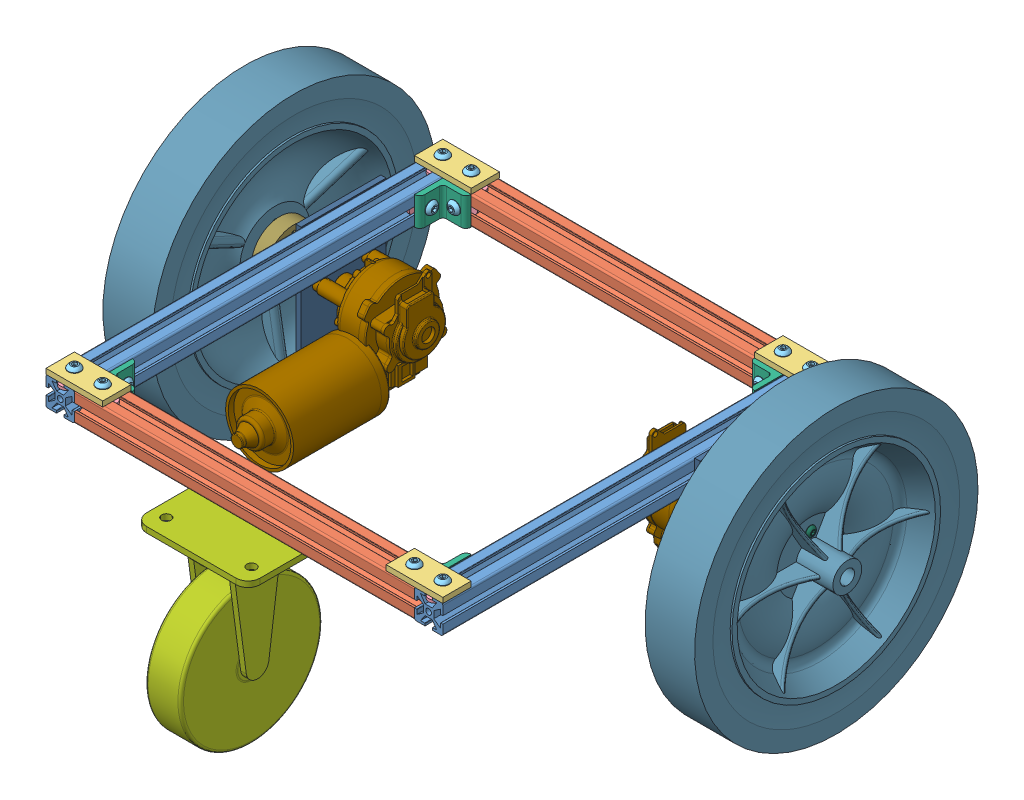
SolidWorks assembly Mobile Platform and Wheels, configuration Default. Lengths in mm.
Overall size (859.25 364.25 511.67).
92 component instances, 15 part files, 61 mates.
Components (placement in the parent):
- mobile platform-1: mobile platform [Default] at (-34.0492 217.8282 272.4297) size (581.47 166.45 355.6)
  - 80-20 Extrusion- 14in-1: 80-20 Extrusion- 14in [80-20 Extrusion - 12.0 inch] at (360.9878 12.7 -25.4) size (25.4 25.4 355.6)
  - 80-20 Extrusion -12in-1: 80-20 Extrusion -12in [80-20 Extrusion - 12.0 inch] at (348.2878 12.7 317.5) x (0 0 1) z (-1 0 0) size (25.4 25.4 304.8)
  - 80-20 Extrusion -12in-2: 80-20 Extrusion -12in [80-20 Extrusion - 12.0 inch] at (348.2878 12.7 -12.7) x (0 0 1) z (-1 0 0) size (25.4 25.4 304.8)
  - 80-20 Straight Degree Bracket Assy-2: 80-20 Straight Degree Bracket Assy [Default] at (308.9247 -2.3915 0.8462) x (0 0 -1) z (1 0 0) size (25.4 16.05 50.8)
    - 80-20 Straight Bracket-1: 80-20 Straight Bracket [Default] at (0.8462 27.7915 64.7631) size (25.4 4.76 50.8)
    - 80-20 0.25-20 T-NUT-1: 80-20 0.25-20 T-NUT [Default] at (139.4792 22.117 145.0157) x (0 0 -1) z (0 1 0) size (25.4 11.25 2.41)
    - 0.25-20 Button Head Cap Screw (BHCS)-1: 0.25-20 Button Head Cap Screw (BHCS) [Default] at (13.5462 35.9068 26.6631) x (1 0 0) z (0 -1 0) size (11.1 11.1 16.05)
    - 0.25-20 Button Head Cap Screw (BHCS)-2: 0.25-20 Button Head Cap Screw (BHCS) [Default] at (13.5462 35.9068 52.0631) x (-0.336886 0 -0.941545) z (0 -1 0) size (11.1 11.1 16.05)
    - 80-20 0.25-20 T-NUT-2: 80-20 0.25-20 T-NUT [Default] at (131.8987 22.8031 -73.87) x (-1 0 0) z (0 1 0) size (25.4 11.25 2.41)
  - 80-20 Straight Degree Bracket Assy-3: 80-20 Straight Degree Bracket Assy [Default] at (308.9247 -2.3915 331.0462) x (0 0 -1) z (1 0 0) size (25.4 16.05 50.8)
    - 80-20 Straight Bracket-1: 80-20 Straight Bracket [Default] at (0.8462 27.7915 64.7631) size (25.4 4.76 50.8)
    - 80-20 0.25-20 T-NUT-1: 80-20 0.25-20 T-NUT [Default] at (139.4792 22.117 145.0157) x (0 0 -1) z (0 1 0) size (25.4 11.25 2.41)
    - 0.25-20 Button Head Cap Screw (BHCS)-1: 0.25-20 Button Head Cap Screw (BHCS) [Default] at (13.5462 35.9068 26.6631) x (1 0 0) z (0 -1 0) size (11.1 11.1 16.05)
    - 0.25-20 Button Head Cap Screw (BHCS)-2: 0.25-20 Button Head Cap Screw (BHCS) [Default] at (13.5462 35.9068 52.0631) x (-0.336886 0 -0.941545) z (0 -1 0) size (11.1 11.1 16.05)
    - 80-20 0.25-20 T-NUT-2: 80-20 0.25-20 T-NUT [Default] at (131.8987 22.8031 -73.87) x (-1 0 0) z (0 1 0) size (25.4 11.25 2.41)
  - 80-20 90 Degree Bracket Assy-1: 80-20 90 Degree Bracket Assy [Default] at (41.0093 16.2711 -8.6086) x (0 -1 0) z (0 0 1) size (25.4 35.88 33.34)
    - 80-20 90 Degree Angle Bracket-1: 80-20 90 Degree Angle Bracket [Default] at (-9.1289 2.4785 8.6086) size (25.4 25.4 25.4)
    - 0.25-20 Button Head Cap Screw (BHCS)-1: 0.25-20 Button Head Cap Screw (BHCS) [Default] at (3.5711 10.5938 23.8486) x (1 0 0) z (0 -1 0) size (11.1 11.1 16.05)
    - 0.25-20 Button Head Cap Screw (BHCS)-2: 0.25-20 Button Head Cap Screw (BHCS) [Default] at (3.5711 17.7185 16.7239) x (1 0 0) z (0 0 -1) size (11.1 11.1 16.05)
    - 80-20 0.25-20 T-NUT-2: 80-20 0.25-20 T-NUT [Default] at (-122.3619 -100.634 5.3515) x (0 1 0) z (0 0 -1) size (25.4 11.25 2.41)
  - 80-20 90 Degree Bracket Assy-2: 80-20 90 Degree Bracket Assy [Default] at (356.8964 9.1289 307.2785) x (0 1 0) z (-1 0 0) size (25.4 35.88 33.34)
    - 80-20 90 Degree Angle Bracket-1: 80-20 90 Degree Angle Bracket [Default] at (-9.1289 2.4785 8.6086) size (25.4 25.4 25.4)
    - 0.25-20 Button Head Cap Screw (BHCS)-1: 0.25-20 Button Head Cap Screw (BHCS) [Default] at (3.5711 10.5938 23.8486) x (1 0 0) z (0 -1 0) size (11.1 11.1 16.05)
    - 0.25-20 Button Head Cap Screw (BHCS)-2: 0.25-20 Button Head Cap Screw (BHCS) [Default] at (3.5711 17.7185 16.7239) x (1 0 0) z (0 0 -1) size (11.1 11.1 16.05)
    - 80-20 0.25-20 T-NUT-2: 80-20 0.25-20 T-NUT [Default] at (-122.3619 -100.634 5.3515) x (0 1 0) z (0 0 -1) size (25.4 11.25 2.41)
  - 80-20 90 Degree Bracket Assy-3: 80-20 90 Degree Bracket Assy [Default] at (350.7663 9.1289 -8.6086) x (0 1 0) z (0 0 1) size (25.4 35.88 33.34)
    - 80-20 90 Degree Angle Bracket-1: 80-20 90 Degree Angle Bracket [Default] at (-9.1289 2.4785 8.6086) size (25.4 25.4 25.4)
    - 0.25-20 Button Head Cap Screw (BHCS)-1: 0.25-20 Button Head Cap Screw (BHCS) [Default] at (3.5711 10.5938 23.8486) x (1 0 0) z (0 -1 0) size (11.1 11.1 16.05)
    - 0.25-20 Button Head Cap Screw (BHCS)-2: 0.25-20 Button Head Cap Screw (BHCS) [Default] at (3.5711 17.7185 16.7239) x (1 0 0) z (0 0 -1) size (11.1 11.1 16.05)
    - 80-20 0.25-20 T-NUT-2: 80-20 0.25-20 T-NUT [Default] at (-122.3619 -100.634 5.3515) x (0 1 0) z (0 0 -1) size (25.4 11.25 2.41)
  - 80-20 90 Degree Bracket Assy-4: 80-20 90 Degree Bracket Assy [Default] at (35.9499 16.2711 307.2785) x (0 -1 0) z (1 0 0) size (25.4 35.88 33.34)
    - 80-20 90 Degree Angle Bracket-1: 80-20 90 Degree Angle Bracket [Default] at (-9.1289 2.4785 8.6086) size (25.4 25.4 25.4)
    - 0.25-20 Button Head Cap Screw (BHCS)-1: 0.25-20 Button Head Cap Screw (BHCS) [Default] at (3.5711 10.5938 23.8486) x (1 0 0) z (0 -1 0) size (11.1 11.1 16.05)
    - 0.25-20 Button Head Cap Screw (BHCS)-2: 0.25-20 Button Head Cap Screw (BHCS) [Default] at (3.5711 17.7185 16.7239) x (1 0 0) z (0 0 -1) size (11.1 11.1 16.05)
    - 80-20 0.25-20 T-NUT-2: 80-20 0.25-20 T-NUT [Default] at (-122.3619 -100.634 5.3515) x (0 1 0) z (0 0 -1) size (25.4 11.25 2.41)
  - 80-20 Extrusion- 14in-2: 80-20 Extrusion- 14in [80-20 Extrusion - 12.0 inch] at (30.7878 12.7 -25.4) size (25.4 25.4 355.6)
  - 80-20 Straight Degree Bracket Assy-4: 80-20 Straight Degree Bracket Assy [Default] at (82.8509 -2.3915 -26.2462) x (0 0 1) z (-1 0 0) size (25.4 16.05 50.8)
    - 80-20 Straight Bracket-1: 80-20 Straight Bracket [Default] at (0.8462 27.7915 64.7631) size (25.4 4.76 50.8)
    - 80-20 0.25-20 T-NUT-1: 80-20 0.25-20 T-NUT [Default] at (139.4792 22.117 145.0157) x (0 0 -1) z (0 1 0) size (25.4 11.25 2.41)
    - 0.25-20 Button Head Cap Screw (BHCS)-1: 0.25-20 Button Head Cap Screw (BHCS) [Default] at (13.5462 35.9068 26.6631) x (1 0 0) z (0 -1 0) size (11.1 11.1 16.05)
    - 0.25-20 Button Head Cap Screw (BHCS)-2: 0.25-20 Button Head Cap Screw (BHCS) [Default] at (13.5462 35.9068 52.0631) x (-0.336886 0 -0.941545) z (0 -1 0) size (11.1 11.1 16.05)
    - 80-20 0.25-20 T-NUT-2: 80-20 0.25-20 T-NUT [Default] at (131.8987 22.8031 -73.87) x (-1 0 0) z (0 1 0) size (25.4 11.25 2.41)
  - 80-20 Straight Degree Bracket Assy-5: 80-20 Straight Degree Bracket Assy [Default] at (82.8509 -2.3915 303.9538) x (0 0 1) z (-1 0 0) size (25.4 16.05 50.8)
    - 80-20 Straight Bracket-1: 80-20 Straight Bracket [Default] at (0.8462 27.7915 64.7631) size (25.4 4.76 50.8)
    - 80-20 0.25-20 T-NUT-1: 80-20 0.25-20 T-NUT [Default] at (139.4792 22.117 145.0157) x (0 0 -1) z (0 1 0) size (25.4 11.25 2.41)
    - 0.25-20 Button Head Cap Screw (BHCS)-1: 0.25-20 Button Head Cap Screw (BHCS) [Default] at (13.5462 35.9068 26.6631) x (1 0 0) z (0 -1 0) size (11.1 11.1 16.05)
    - 0.25-20 Button Head Cap Screw (BHCS)-2: 0.25-20 Button Head Cap Screw (BHCS) [Default] at (13.5462 35.9068 52.0631) x (-0.336886 0 -0.941545) z (0 -1 0) size (11.1 11.1 16.05)
    - 80-20 0.25-20 T-NUT-2: 80-20 0.25-20 T-NUT [Default] at (131.8987 22.8031 -73.87) x (-1 0 0) z (0 1 0) size (25.4 11.25 2.41)
  - 80-20 0.25-20 T-NUT-1: 80-20 0.25-20 T-NUT [Default] at (214.6952 -113.2331 306.9864) size (25.4 11.25 2.41)
  - 80-20 0.25-20 T-NUT-2: 80-20 0.25-20 T-NUT [Default] at (-58.5541 -113.2331 306.9864) size (25.4 11.25 2.41)
  - 80-20 0.25-20 T-NUT-3: 80-20 0.25-20 T-NUT [Default] at (41.3014 -113.2331 -103.1126) x (0 0 1) z (-1 0 0) size (25.4 11.25 2.41)
  - 80-20 0.25-20 T-NUT-4: 80-20 0.25-20 T-NUT [Default] at (350.4742 -113.2331 133.5926) x (0 0 -1) z (1 0 0) size (25.4 11.25 2.41)
- 0.25-20 Button Head Cap Screw (BHCS)-1: 0.25-20 Button Head Cap Screw (BHCS) [Default] at (-24.0767 230.5282 316.8797) x (0 -0.87127 -0.490804) z (1 0 0) size (11.1 11.1 16.05)
- 0.25-20 Button Head Cap Screw (BHCS)-2: 0.25-20 Button Head Cap Screw (BHCS) [Default] at (-24.0767 230.5282 354.9797) x (0 -0.925607 -0.378485) z (1 0 0) size (11.1 11.1 16.05)
- 0.25-20 Button Head Cap Screw (BHCS)-3: 0.25-20 Button Head Cap Screw (BHCS) [Default] at (347.7539 230.5282 319.7734) x (0 0.895902 0.444252) z (-1 0 0) size (11.1 11.1 16.05)
- 0.25-20 Button Head Cap Screw (BHCS)-4: 0.25-20 Button Head Cap Screw (BHCS) [Default] at (347.7539 230.5282 357.8734) x (0 0.519927 -0.854211) z (-1 0 0) size (11.1 11.1 16.05)
- 80-20 0.25-20 T-NUT-1: 80-20 0.25-20 T-NUT [Default] at (337.4522 104.5951 201.4209) x (0 0 1) z (-1 0 0) size (25.4 11.25 2.41)
- 80-20 0.25-20 T-NUT-2: 80-20 0.25-20 T-NUT [Default] at (-13.775 104.5951 435.2323) x (0 0 -1) z (1 0 0) size (25.4 11.25 2.41)
- 80-20 0.25-20 T-NUT-3: 80-20 0.25-20 T-NUT [Default] at (-13.775 104.5951 473.3323) x (0 0 -1) z (1 0 0) size (25.4 11.25 2.41)
- 80-20 0.25-20 T-NUT-4: 80-20 0.25-20 T-NUT [Default] at (337.4522 356.4612 476.226) x (0 0 -1) z (-1 0 0) size (25.4 11.25 2.41)
- Caster Wheel-1: Caster Wheel [Default] at (161.8386 217.8282 612.0617) x (-1 0 0) z (0 0 1) size (101.6 160.02 127)
- 80-20 0.25-20 T-NUT-5: 80-20 0.25-20 T-NUT [Default] at (5.2717 222.3788 463.7893) x (1 0 0) z (0 -1 0) size (25.4 11.25 2.41)
- 80-20 0.25-20 T-NUT-6: 80-20 0.25-20 T-NUT [Default] at (81.7003 222.3788 463.7893) x (1 0 0) z (0 -1 0) size (25.4 11.25 2.41)
- 0.25X20- 0.375in Cap Screw-1: 0.25X20- 0.375in Cap Screw [97763A262] at (123.6243 209.3954 589.7224) x (-0.984842 0 0.173455) z (0 -1 0) size (11.1 11.1 13.11)
- 0.25X20- 0.375in Cap Screw-2: 0.25X20- 0.375in Cap Screw [97763A262] at (200.0529 209.3954 589.7224) x (0.999999 0 -0.001416) z (0 -1 0) size (11.1 11.1 13.11)
- Enstort Bracket + Wheel Hub Assembly-1: Enstort Bracket + Wheel Hub Assembly [Entstort Bracket + Wheel Hub Assembly] at (136.9487 78.0176 331.0106) x (0 0 1) z (-1 0 0) size (175.66 126.24 332.48)
  - motor bracket assembly-1: motor bracket assembly [Default] at (-11.3939 -3.7311 8.9529) size (175.66 126.24 116.01)
    - 44 RPM Entstort Right Angle Gear Motor-1: 44 RPM Entstort Right Angle Gear Motor [Default] at (75.065 73.1836 102.1742) size (170.1 101.53 116.01)
    - bracket motor mount-1: bracket motor mount [Default] at (-21.7871 168.9416 143.9572) x (0 -1 0) z (0 0 1) size (101.6 76.2 4.76)
    - M6X1mm-10mm Hex Head-1: M6X1mm-10mm Hex Head [91287A133] at (39.7568 118.1416 145.7197) x (0 0 -1) z (-0.053654 -0.99856 0) size (14 11.55 10)
    - M6X1mm-10mm Hex Head-2: M6X1mm-10mm Hex Head [91287A133] at (-4.2372 118.1416 145.7197) x (0 0 -1) z (0.587181 -0.809455 0) size (14 11.55 10)
    - M6X1mm-10mm Hex Head-3: M6X1mm-10mm Hex Head [91287A133] at (17.7598 80.0416 145.7197) x (0 0 -1) z (0.923728 0.383049 0) size (14 11.55 10)
  - Wheel Hub-1: Wheel Hub [Default] at (6.3659 101.7105 208.8272) x (-1 0 0) z (0 0 -1) size (50.8 50.8 38.1)
  - M8 Hex Nut-1: M8 Hex Nut [90592A022] at (6.3659 101.7105 189.2172) size (13 15.01 6.5)
- Enstort Bracket + Wheel Hub Assembly-2: Enstort Bracket + Wheel Hub Assembly [Entstort Bracket + Wheel Hub Assembly] at (186.7285 78.0176 343.7425) x (0 0 -1) z (1 0 0) size (175.66 126.24 332.48)
  - motor bracket assembly-1: motor bracket assembly [Default] at (-11.3939 -3.7311 8.9529) size (175.66 126.24 116.01)
    - 44 RPM Entstort Right Angle Gear Motor-1: 44 RPM Entstort Right Angle Gear Motor [Default] at (75.065 73.1836 102.1742) size (170.1 101.53 116.01)
    - bracket motor mount-1: bracket motor mount [Default] at (-21.7871 168.9416 143.9572) x (0 -1 0) z (0 0 1) size (101.6 76.2 4.76)
    - M6X1mm-10mm Hex Head-1: M6X1mm-10mm Hex Head [91287A133] at (39.7568 118.1416 145.7197) x (0 0 -1) z (-0.053654 -0.99856 0) size (14 11.55 10)
    - M6X1mm-10mm Hex Head-2: M6X1mm-10mm Hex Head [91287A133] at (-4.2372 118.1416 145.7197) x (0 0 -1) z (0.587181 -0.809455 0) size (14 11.55 10)
    - M6X1mm-10mm Hex Head-3: M6X1mm-10mm Hex Head [91287A133] at (17.7598 80.0416 145.7197) x (0 0 -1) z (0.923728 0.383049 0) size (14 11.55 10)
  - Wheel Hub-1: Wheel Hub [Default] at (6.3659 101.7105 208.8272) x (-1 0 0) z (0 0 -1) size (50.8 50.8 38.1)
  - M8 Hex Nut-1: M8 Hex Nut [90592A022] at (6.3659 101.7105 189.2172) size (13 15.01 6.5)
- 10 Inch Wheel-1: 10 Inch Wheel [Default] at (-86.0518 179.7282 337.3766) x (-1 0 0) z (0 -0.5 0.866025) size (54.2 254 254)
- 10 Inch Wheel-2: 10 Inch Wheel [Default] at (409.7289 179.7282 337.3766) x (1 0 0) z (0 -0.5 0.866025) size (54.2 254 254)
- 10X24 -0.75in Cap Screw-1: 10X24 -0.75in Cap Screw [97763A337] at (-82.699 170.2032 353.8744) x (0 0.124315 -0.992243) z (-1 0 0) size (9.17 9.17 21.8)
- 10X24 -0.75in Cap Screw-2: 10X24 -0.75in Cap Screw [97763A337] at (-82.699 170.2032 320.8788) x (0 0.987183 -0.159589) z (-1 0 0) size (9.17 9.17 21.8)
- 10X24 -0.75in Cap Screw-3: 10X24 -0.75in Cap Screw [97763A337] at (-82.699 198.7782 337.3766) x (0 0.987183 -0.159589) z (-1 0 0) size (9.17 9.17 21.8)
- 10X24 -0.75in Cap Screw-4: 10X24 -0.75in Cap Screw [97763A337] at (406.3761 170.2032 353.8744) x (0 -0.05419 -0.998531) z (1 0 0) size (9.17 9.17 21.8)
- 10X24 -0.75in Cap Screw-5: 10X24 -0.75in Cap Screw [97763A337] at (406.3761 198.7782 337.3766) x (0 -0.05419 -0.998531) z (1 0 0) size (9.17 9.17 21.8)
- 10X24 -0.75in Cap Screw-6: 10X24 -0.75in Cap Screw [97763A337] at (406.3761 170.2032 320.8788) x (0 -0.05419 -0.998531) z (1 0 0) size (9.17 9.17 21.8)
Mates (geometry in assembly coordinates):
- Concentric6: concentric anti-aligned: cylinder of 0.25-20 Button Head Cap Screw (BHCS)-1 through (-8.0239 230.5282 316.8797) axis (-1 0 0) radius 3.175; cylinder of 80-20 0.25-20 T-NUT-2 through (-13.776 230.5282 316.8797) axis (1 0 0) radius 3.175
- Parallel3: parallel: line of 80-20 0.25-20 T-NUT-2 through (-13.775 236.1543 309.8058) axis (0 0 1); plane of mobile platform-1/80-20 Extrusion- 14in-2 through (-3.3102 233.7433 230.2906) normal (0 -1 0)
- Coincident16: coincident anti-aligned: plane of mobile platform-1/80-20 Extrusion- 14in-2 through (-13.775 230.4794 230.2906) normal (1 0 0); plane of 80-20 0.25-20 T-NUT-2 through (-13.775 230.5282 323.9536) normal (-1 0 0)
- Concentric8: concentric anti-aligned: cylinder of 0.25-20 Button Head Cap Screw (BHCS)-2 through (-8.0239 230.5282 354.9797) axis (-1 0 0) radius 3.175; cylinder of 80-20 0.25-20 T-NUT-3 through (-13.776 230.5282 354.9797) axis (1 0 0) radius 3.175
- Parallel4: parallel: line of 80-20 0.25-20 T-NUT-3 through (-13.775 236.1543 347.9058) axis (0 0 1); plane of mobile platform-1/80-20 Extrusion- 14in-2 through (-3.3102 233.7433 230.2906) normal (0 -1 0)
- Concentric11: concentric anti-aligned: cylinder of 0.25-20 Button Head Cap Screw (BHCS)-3 through (331.7011 230.5282 319.7734) axis (1 0 0) radius 3.175; cylinder of 80-20 0.25-20 T-NUT-1 through (337.4532 230.5282 319.7734) axis (-1 0 0) radius 3.175
- Concentric12: concentric anti-aligned: cylinder of 0.25-20 Button Head Cap Screw (BHCS)-4 through (331.7011 230.5282 357.8734) axis (1 0 0) radius 3.175; cylinder of 80-20 0.25-20 T-NUT-4 through (337.4532 230.5282 357.8734) axis (-1 0 0) radius 3.175
- Parallel5: parallel: plane of mobile platform-1/80-20 Extrusion- 14in-1 through (314.2386 243.2282 602.6297) normal (0 1 0); line of 80-20 0.25-20 T-NUT-4 through (337.4522 236.1543 364.9473) axis (0 0 -1)
- Coincident26: coincident anti-aligned: plane of mobile platform-1/80-20 Extrusion- 14in-1 through (337.4522 230.4794 230.2906) normal (-1 0 0); plane of 80-20 0.25-20 T-NUT-4 through (337.4522 230.5282 364.9473) normal (1 0 0)
- Parallel6: parallel: plane of mobile platform-1/80-20 Extrusion- 14in-1 through (314.2386 243.2282 602.6297) normal (0 1 0); line of 80-20 0.25-20 T-NUT-1 through (337.4522 236.1543 326.8473) axis (0 0 -1)
- Coincident29: coincident anti-aligned: plane of mobile platform-1/80-20 Extrusion- 14in-1 through (337.4522 230.4794 230.2906) normal (-1 0 0); plane of 80-20 0.25-20 T-NUT-1 through (337.4522 230.5282 312.6995) normal (1 0 0)
- Coincident34: coincident anti-aligned: plane of mobile platform-1/80-20 Extrusion -12in-1 through (9.4386 217.8282 577.2297) normal (0 -1 0); plane of Caster Wheel-1 through (201.9706 217.8282 639.4937) normal (0 1 0)
- Parallel7: parallel anti-aligned: plane of mobile platform-1/80-20 Extrusion -12in-1 through (9.4386 217.8282 602.6297) normal (0 0 1); plane of Caster Wheel-1 through (201.9706 212.7482 573.9617) normal (0 0 -1)
- Distance3: distance = 3.268 mm aligned: plane of mobile platform-1/80-20 Extrusion -12in-1 through (9.4386 217.8282 577.2297) normal (0 0 -1); plane of Caster Wheel-1 through (201.9706 212.7482 573.9617) normal (0 0 -1)
- Parallel8: parallel aligned: plane of mobile platform-1/80-20 Extrusion -12in-1 through (9.4386 217.8282 602.6297) normal (0 0 1); plane of 80-20 0.25-20 T-NUT-5 through (116.5504 219.9658 595.3485) normal (0 0 1)
- Coincident40: coincident anti-aligned: plane of mobile platform-1/80-20 Extrusion -12in-1 through (330.9777 219.9658 589.9297) normal (0 1 0); plane of 80-20 0.25-20 T-NUT-5 through (116.5504 219.9658 589.7224) normal (0 -1 0)
- Parallel9: parallel aligned: plane of mobile platform-1/80-20 Extrusion -12in-1 through (9.4386 217.8282 602.6297) normal (0 0 1); plane of 80-20 0.25-20 T-NUT-6 through (192.979 219.9658 595.3485) normal (0 0 1)
- Coincident44: coincident anti-aligned: plane of mobile platform-1/80-20 Extrusion -12in-1 through (330.9777 219.9658 589.9297) normal (0 1 0); plane of 80-20 0.25-20 T-NUT-6 through (192.979 219.9658 589.7224) normal (0 -1 0)
- Parallel10: parallel aligned: plane of mobile platform-1/80-20 Extrusion- 14in-2 through (-15.9614 243.2282 602.6297) normal (0 1 0); plane of 80-20 0.25-20 T-NUT-2 through (-11.362 236.1543 323.9536) normal (0 1 0)
- Coincident49: coincident anti-aligned: plane of mobile platform-1/80-20 Extrusion- 14in-2 through (-13.775 230.4794 230.2906) normal (1 0 0); plane of 80-20 0.25-20 T-NUT-2 through (-13.775 230.5282 323.9536) normal (-1 0 0)
- Parallel11: parallel: plane of mobile platform-1/80-20 Extrusion- 14in-2 through (-15.9614 243.2282 602.6297) normal (0 1 0); line of 80-20 0.25-20 T-NUT-3 through (-13.775 236.1543 347.9058) axis (0 0 1)
- Coincident51: coincident anti-aligned: plane of mobile platform-1/80-20 Extrusion- 14in-2 through (-13.775 230.4794 230.2906) normal (1 0 0); plane of 80-20 0.25-20 T-NUT-3 through (-13.775 230.5282 362.0536) normal (-1 0 0)
- Distance7: distance = 127 mm: line of Caster Wheel-1 through (111.0386 217.8282 639.4937) axis (0 0 -1); plane of mobile platform-1/80-20 Extrusion- 14in-2 through (-15.9614 217.8282 602.6297) normal (-1 0 0)
- Concentric16: concentric anti-aligned: circle of 80-20 0.25-20 T-NUT-5; cylinder of 0.25X20- 0.375in Cap Screw-1 through (123.6243 222.2732 589.7224) axis (0 1 0) radius 3.175
- Concentric17: concentric anti-aligned: circle of Caster Wheel-1; cylinder of 0.25X20- 0.375in Cap Screw-2 through (200.0529 222.2732 589.7224) axis (0 1 0) radius 3.175
- Coincident54: coincident anti-aligned: plane of Caster Wheel-1 through (201.9706 212.7482 639.4937) normal (0 -1 0); plane of 0.25X20- 0.375in Cap Screw-1 through (124.5869 212.7482 595.1882) normal (0 1 0)
- Coincident55: coincident anti-aligned: plane of Caster Wheel-1 through (201.9706 212.7482 639.4937) normal (0 -1 0); plane of 0.25X20- 0.375in Cap Screw-2 through (200.045 212.7482 584.1725) normal (0 1 0)
- Concentric22: concentric aligned: cylinder of Caster Wheel-1 through (123.6243 212.7482 589.7224) axis (0 1 0) radius 4.2164; cylinder of 0.25X20- 0.375in Cap Screw-1 through (123.6243 222.2732 589.7224) axis (0 1 0) radius 3.175
- Concentric23: concentric anti-aligned: cylinder of 80-20 0.25-20 T-NUT-6 through (200.0529 222.3798 589.7224) axis (0 -1 0) radius 3.175; cylinder of 0.25X20- 0.375in Cap Screw-2 through (200.0529 222.2732 589.7224) axis (0 1 0) radius 3.175
- Coincident56: coincident aligned: plane of mobile platform-1/80-20 Extrusion- 14in-2 through (-15.9614 243.2282 602.6297) normal (0 1 0); plane of Enstort Bracket + Wheel Hub Assembly-1/motor bracket assembly-1/bracket motor mount-1 through (-20.7239 243.2282 374.0297) normal (0 1 0)
- Coincident57: coincident anti-aligned: plane of mobile platform-1/80-20 Extrusion- 14in-2 through (-15.9614 217.8282 602.6297) normal (-1 0 0); plane of Enstort Bracket + Wheel Hub Assembly-1/motor bracket assembly-1/bracket motor mount-1 through (-15.9614 243.2282 297.8297) normal (1 0 0)
- Distance8: distance = 50.8 mm aligned: plane of Enstort Bracket + Wheel Hub Assembly-1/motor bracket assembly-1/bracket motor mount-1 through (-20.7239 243.2282 297.8297) normal (0 0 -1); plane of mobile platform-1/80-20 Extrusion- 14in-2 through (9.4386 243.2282 247.0297) normal (0 0 -1)
- Concentric24: concentric aligned: cylinder of 0.25-20 Button Head Cap Screw (BHCS)-1 through (-8.0239 230.5282 316.8797) axis (-1 0 0) radius 3.175; cylinder of Enstort Bracket + Wheel Hub Assembly-1/motor bracket assembly-1/bracket motor mount-1 through (-15.9614 230.5282 316.8797) axis (-1 0 0) radius 3.3782
- Coincident59: coincident anti-aligned: plane of 0.25-20 Button Head Cap Screw (BHCS)-1 through (-20.7239 225.6927 314.1558) normal (1 0 0); plane of Enstort Bracket + Wheel Hub Assembly-1/motor bracket assembly-1/bracket motor mount-1 through (-20.7239 243.2282 297.8297) normal (-1 0 0)
- Concentric25: concentric aligned: cylinder of 0.25-20 Button Head Cap Screw (BHCS)-2 through (-8.0239 230.5282 354.9797) axis (-1 0 0) radius 3.175; cylinder of Enstort Bracket + Wheel Hub Assembly-1/motor bracket assembly-1/bracket motor mount-1 through (-15.9614 230.5282 354.9797) axis (-1 0 0) radius 3.3782
- Coincident60: coincident anti-aligned: plane of 0.25-20 Button Head Cap Screw (BHCS)-2 through (-20.7239 225.3911 352.8791) normal (1 0 0); plane of Enstort Bracket + Wheel Hub Assembly-1/motor bracket assembly-1/bracket motor mount-1 through (-20.7239 243.2282 297.8297) normal (-1 0 0)
- Concentric41: concentric anti-aligned: cylinder of 10 Inch Wheel-1 through (-58.95 179.7282 337.3766) axis (1 0 0) radius 127; cylinder of 10 Inch Wheel-2 through (382.6271 179.7282 337.3766) axis (-1 0 0) radius 127
- Coincident62: coincident aligned: plane of mobile platform-1/80-20 Extrusion- 14in-1 through (314.2386 243.2282 602.6297) normal (0 1 0); plane of Enstort Bracket + Wheel Hub Assembly-2/motor bracket assembly-1/bracket motor mount-1 through (344.4011 243.2282 300.7234) normal (0 1 0)
- Coincident63: coincident anti-aligned: plane of mobile platform-1/80-20 Extrusion- 14in-1 through (339.6386 217.8282 602.6297) normal (1 0 0); plane of Enstort Bracket + Wheel Hub Assembly-2/motor bracket assembly-1/bracket motor mount-1 through (339.6386 243.2282 376.9234) normal (-1 0 0)
- Concentric26: concentric aligned: cylinder of 0.25-20 Button Head Cap Screw (BHCS)-3 through (331.7011 230.5282 319.7734) axis (1 0 0) radius 3.175; cylinder of Enstort Bracket + Wheel Hub Assembly-2/motor bracket assembly-1/bracket motor mount-1 through (339.6386 230.5282 319.7734) axis (1 0 0) radius 3.3782
- Coincident64: coincident anti-aligned: plane of 0.25-20 Button Head Cap Screw (BHCS)-3 through (344.4011 235.5003 322.239) normal (-1 0 0); plane of Enstort Bracket + Wheel Hub Assembly-2/motor bracket assembly-1/bracket motor mount-1 through (344.4011 243.2282 376.9234) normal (1 0 0)
- Concentric27: concentric aligned: cylinder of 0.25-20 Button Head Cap Screw (BHCS)-4 through (331.7011 230.5282 357.8734) axis (1 0 0) radius 3.175; cylinder of Enstort Bracket + Wheel Hub Assembly-2/motor bracket assembly-1/bracket motor mount-1 through (339.6386 230.5282 357.8734) axis (1 0 0) radius 3.3782
- Coincident65: coincident anti-aligned: plane of 0.25-20 Button Head Cap Screw (BHCS)-4 through (344.4011 233.4137 353.1327) normal (-1 0 0); plane of Enstort Bracket + Wheel Hub Assembly-2/motor bracket assembly-1/bracket motor mount-1 through (344.4011 243.2282 376.9234) normal (1 0 0)
- Coincident66: coincident anti-aligned: plane of Enstort Bracket + Wheel Hub Assembly-1/Wheel Hub-1 through (-71.8786 179.7282 337.3766) normal (-1 0 0); plane of 10 Inch Wheel-1 through (-71.8786 164.8801 328.8041) normal (1 0 0)
- Concentric28: concentric anti-aligned: cylinder of Enstort Bracket + Wheel Hub Assembly-1/Wheel Hub-1 through (-71.8786 198.7782 337.3766) axis (-1 0 0) radius 1.8986; cylinder of 10 Inch Wheel-1 through (-71.8786 198.7782 337.3766) axis (1 0 0) radius 2.4892
- Concentric29: concentric anti-aligned: cylinder of Enstort Bracket + Wheel Hub Assembly-1/Wheel Hub-1 through (-71.8786 170.2032 353.8744) axis (-1 0 0) radius 1.8986; cylinder of 10 Inch Wheel-1 through (-71.8786 170.2032 353.8744) axis (1 0 0) radius 2.4892
- Coincident67: coincident anti-aligned: plane of Enstort Bracket + Wheel Hub Assembly-2/Wheel Hub-1 through (395.5557 179.7282 337.3766) normal (1 0 0); plane of 10 Inch Wheel-2 through (395.5557 194.5762 345.9491) normal (-1 0 0)
- Concentric30: concentric anti-aligned: cylinder of Enstort Bracket + Wheel Hub Assembly-2/Wheel Hub-1 through (395.5557 198.7782 337.3766) axis (1 0 0) radius 1.8986; cylinder of 10 Inch Wheel-2 through (395.5557 198.7782 337.3766) axis (-1 0 0) radius 2.4892
- Concentric31: concentric anti-aligned: cylinder of Enstort Bracket + Wheel Hub Assembly-2/Wheel Hub-1 through (395.5557 170.2032 320.8788) axis (1 0 0) radius 1.8986; cylinder of 10 Inch Wheel-2 through (395.5557 170.2032 320.8788) axis (-1 0 0) radius 2.4892
- Concentric35: concentric aligned: cylinder of 10 Inch Wheel-1 through (-71.8786 198.7782 337.3766) axis (1 0 0) radius 2.4892; cylinder of 10X24 -0.75in Cap Screw-3 through (-61.0836 198.7782 337.3766) axis (1 0 0) radius 2.413
- Concentric36: concentric aligned: cylinder of 10 Inch Wheel-1 through (-71.8786 170.2032 320.8788) axis (1 0 0) radius 2.4892; cylinder of 10X24 -0.75in Cap Screw-2 through (-61.0836 170.2032 320.8788) axis (1 0 0) radius 2.413
- Concentric37: concentric aligned: cylinder of 10 Inch Wheel-1 through (-71.8786 170.2032 353.8744) axis (1 0 0) radius 2.4892; cylinder of 10X24 -0.75in Cap Screw-1 through (-61.0836 170.2032 353.8744) axis (1 0 0) radius 2.413
- Coincident71: coincident anti-aligned: plane of 10 Inch Wheel-1 through (-80.1336 168.5317 330.9123) normal (-1 0 0); plane of 10X24 -0.75in Cap Screw-3 through (-80.1336 199.5098 341.9025) normal (1 0 0)
- Coincident72: coincident anti-aligned: plane of 10 Inch Wheel-1 through (-80.1336 168.5317 330.9123) normal (-1 0 0); plane of 10X24 -0.75in Cap Screw-2 through (-80.1336 170.9348 325.4047) normal (1 0 0)
- Coincident73: coincident anti-aligned: plane of 10 Inch Wheel-1 through (-80.1336 168.5317 330.9123) normal (-1 0 0); plane of 10X24 -0.75in Cap Screw-1 through (-80.1336 174.7523 354.4443) normal (1 0 0)
- Concentric38: concentric aligned: cylinder of 10 Inch Wheel-2 through (395.5557 198.7782 337.3766) axis (-1 0 0) radius 2.4892; cylinder of 10X24 -0.75in Cap Screw-5 through (384.7607 198.7782 337.3766) axis (-1 0 0) radius 2.413
- Concentric39: concentric aligned: cylinder of 10 Inch Wheel-2 through (395.5557 170.2032 353.8744) axis (-1 0 0) radius 2.4892; cylinder of 10X24 -0.75in Cap Screw-4 through (384.7607 170.2032 353.8744) axis (-1 0 0) radius 2.413
- Concentric40: concentric aligned: cylinder of 10 Inch Wheel-2 through (395.5557 170.2032 320.8788) axis (-1 0 0) radius 2.4892; cylinder of 10X24 -0.75in Cap Screw-6 through (384.7607 170.2032 320.8788) axis (-1 0 0) radius 2.413
- Coincident74: coincident anti-aligned: plane of 10 Inch Wheel-2 through (403.8107 190.9246 343.8409) normal (1 0 0); plane of 10X24 -0.75in Cap Screw-4 through (403.8107 165.6252 354.1228) normal (-1 0 0)
- Coincident75: coincident anti-aligned: plane of 10 Inch Wheel-2 through (403.8107 190.9246 343.8409) normal (1 0 0); plane of 10X24 -0.75in Cap Screw-5 through (403.8107 194.2002 337.625) normal (-1 0 0)
- Coincident76: coincident anti-aligned: plane of 10 Inch Wheel-2 through (403.8107 190.9246 343.8409) normal (1 0 0); plane of 10X24 -0.75in Cap Screw-6 through (403.8107 165.6252 321.1272) normal (-1 0 0)
